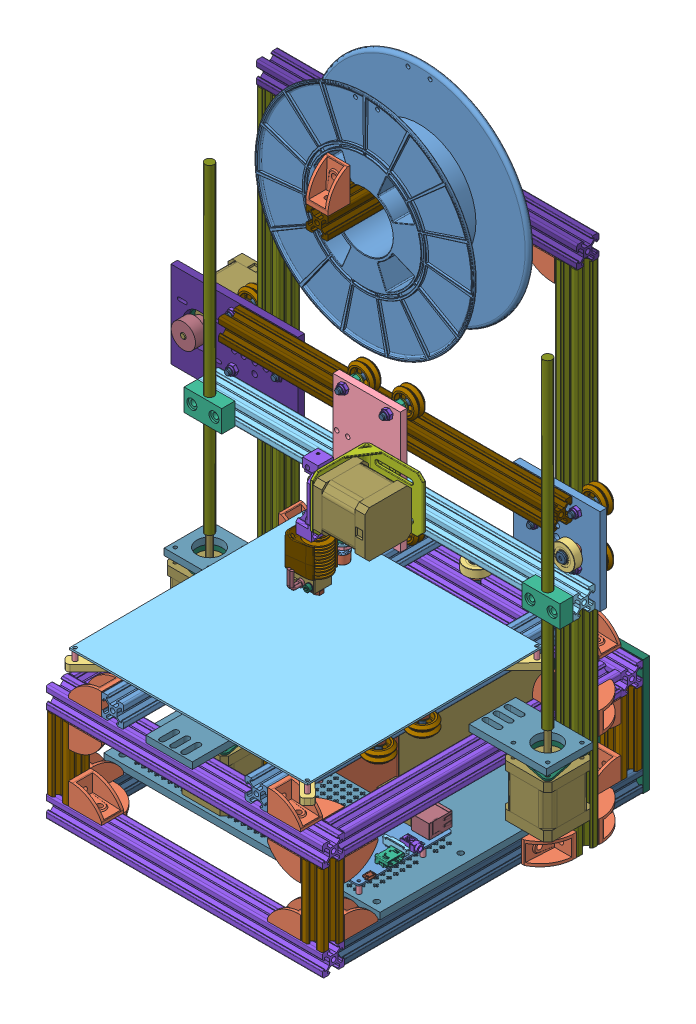
SolidWorks assembly printer, configuration Default. Lengths in mm.
Overall size (437.99 573.71 303.13).
267 component instances, 76 part files, 92 mates.
Components (placement in the parent):
- Y Rail-1: Y Rail [Default] at (13.7265 -1122.1177 248.4377) size (20 20 290)
- Y Rail-2: Y Rail [Default] at (143.7265 -1122.1177 248.4377) size (20 20 290)
- Misumi L bracket-5: Misumi L bracket [Default] at (3.7265 -1132.1177 538.4377) x (0 0 -1) z (0 1 0) size (20 31 21)
- Misumi L bracket-6: Misumi L bracket [Default] at (153.7265 -1132.1177 518.4377) x (0 0 1) z (0 1 0) size (20 31 21)
- y-bed-1: y-bed [Default] at (-21.1202 -1238.0352 260.7176) x (0.99998 0 -0.006342) z (0.006342 0 0.99998) size (222.5 34.74 222.5)
  - y-carriage-1: y-carriage [Default] at (98.8556 128.0325 168.4212) size (222.5 6 222.5)
  - M3 Spacer-1: M3 Spacer [Default] at (-5.6444 134.0325 272.9212) size (4 8 4)
  - M3 Spacer-2: M3 Spacer [Default] at (203.3556 134.0325 63.9212) size (4 8 4)
  - M3 Spacer-3: M3 Spacer [Default] at (203.3556 134.0325 272.9212) size (4 8 4)
  - M3 Spacer-4: M3 Spacer [Default] at (-5.6444 134.0325 63.9212) size (4 8 4)
  - heated-bed-1: heated-bed [Default] at (98.8556 142.0325 168.4212) size (214 1.6 214)
  - Eccentric Delrin Assembly-1: Eccentric Delrin Assembly [Default] at (53.5325 127.0325 167.6503) x (0 -1 0) z (0.219078 0 0.975707) size (31.75 27.59 27.59)
    - Steel Eccentric Spacer-1: Steel Eccentric Spacer [6mm - Mini] at origin size (8.5 9.09 8.71)
    - Precision Shim 10x5x1mm-1: Precision Shim 10x5x1mm [Default] at (6 0 0.79) x (-1 0 0) z (0 0.812589 -0.582837) size (1 10 10)
    - Nylon Insert Hex Locknut M5-1: Nylon Insert Hex Locknut M5 [Default] at (-7 0 0.79) x (0 -0.700969 -0.713192) z (-1 0 0) size (7.68 8.82 4.5)
    - Dual V-Wheel Delrin-1: Dual V-Wheel Delrin [Default] at (11.115 0 0.79) x (0 0.169483 -0.985533) z (1 0 0) size (23.89 23.89 10.23)
    - 5mm Low Profile Socket Head Screw-1: 5mm Low Profile Socket Head Screw [5mm x 30mm Low Profile Screw] at (17.98 0 0.79) x (-1 0 0) z (0 -0.935654 -0.352919) size (31.75 9.5 9.5)
  - Delrin Assembly-1: Delrin Assembly [Default] at (14.0056 122.0325 188.4212) x (0 1 0) z (0.597414 0 0.801933) size (31.75 33.75 33.75)
    - Aluminum Spacer-1: Aluminum Spacer [6mm] at origin size (6 10 10)
    - Precision Shim 10x5x1mm-1: Precision Shim 10x5x1mm [Default] at (-1 0 0) x (1 0 0) z (0 0.993706 0.112022) size (1 10 10)
    - Dual V-Wheel Delrin-1: Dual V-Wheel Delrin [Default] at (-6.115 0 0) x (0 -0.740375 0.672194) z (-1 0 0) size (23.89 23.89 10.23)
    - Nylon Insert Hex Locknut M5-1: Nylon Insert Hex Locknut M5 [Default] at (12 0 0) x (0 -0.231787 0.972767) z (1 0 0) size (7.68 8.82 4.5)
    - 5mm Low Profile Socket Head Screw-1: 5mm Low Profile Socket Head Screw [5mm x 30mm Low Profile Screw] at (-12.98 0 0) x (1 0 0) z (0 0.597414 0.801933) size (31.75 9.5 9.5)
  - Delrin Assembly-2: Delrin Assembly [Default] at (14.0056 122.0325 148.4212) x (0 1 0) z (0.597414 0 0.801933) size (31.75 33.75 33.75)
    - Aluminum Spacer-1: Aluminum Spacer [6mm] at origin size (6 10 10)
    - Precision Shim 10x5x1mm-1: Precision Shim 10x5x1mm [Default] at (-1 0 0) x (1 0 0) z (0 0.993706 0.112022) size (1 10 10)
    - Dual V-Wheel Delrin-1: Dual V-Wheel Delrin [Default] at (-6.115 0 0) x (0 -0.740375 0.672194) z (-1 0 0) size (23.89 23.89 10.23)
    - Nylon Insert Hex Locknut M5-1: Nylon Insert Hex Locknut M5 [Default] at (12 0 0) x (0 -0.231787 0.972767) z (1 0 0) size (7.68 8.82 4.5)
    - 5mm Low Profile Socket Head Screw-1: 5mm Low Profile Socket Head Screw [5mm x 30mm Low Profile Screw] at (-12.98 0 0) x (1 0 0) z (0 0.597414 0.801933) size (31.75 9.5 9.5)
  - Eccentric Delrin Assembly-2: Eccentric Delrin Assembly [Default] at (143.8325 127.0325 167.6503) x (0 -1 0) z (0.219078 0 0.975707) size (31.75 27.59 27.59)
    - Steel Eccentric Spacer-1: Steel Eccentric Spacer [6mm - Mini] at origin size (8.5 9.09 8.71)
    - Precision Shim 10x5x1mm-1: Precision Shim 10x5x1mm [Default] at (6 0 0.79) x (-1 0 0) z (0 0.812589 -0.582837) size (1 10 10)
    - Nylon Insert Hex Locknut M5-1: Nylon Insert Hex Locknut M5 [Default] at (-7 0 0.79) x (0 -0.700969 -0.713192) z (-1 0 0) size (7.68 8.82 4.5)
    - Dual V-Wheel Delrin-1: Dual V-Wheel Delrin [Default] at (11.115 0 0.79) x (0 0.169483 -0.985533) z (1 0 0) size (23.89 23.89 10.23)
    - 5mm Low Profile Socket Head Screw-1: 5mm Low Profile Socket Head Screw [5mm x 30mm Low Profile Screw] at (17.98 0 0.79) x (-1 0 0) z (0 -0.935654 -0.352919) size (31.75 9.5 9.5)
  - Copy of Assem1^y-bed-1: Copy of Assem1^y-bed [Default] at (183.7056 122.0325 148.4212) x (0 1 0) z (0.597414 0 0.801933) size (31.75 33.75 33.75) (virtual)
    - Aluminum Spacer-1: Aluminum Spacer [6mm] at origin size (6 10 10)
    - Precision Shim 10x5x1mm-1: Precision Shim 10x5x1mm [Default] at (-1 0 0) x (1 0 0) z (0 0.993706 0.112022) size (1 10 10)
    - Dual V-Wheel Delrin-1: Dual V-Wheel Delrin [Default] at (-6.115 0 0) x (0 -0.740375 0.672194) z (-1 0 0) size (23.89 23.89 10.23)
    - Nylon Insert Hex Locknut M5-1: Nylon Insert Hex Locknut M5 [Default] at (12 0 0) x (0 -0.231787 0.972767) z (1 0 0) size (7.68 8.82 4.5)
    - 5mm Low Profile Socket Head Screw-1: 5mm Low Profile Socket Head Screw [5mm x 30mm Low Profile Screw] at (-12.98 0 0) x (1 0 0) z (0 0.597414 0.801933) size (31.75 9.5 9.5)
  - Delrin Assembly-4: Delrin Assembly [Default] at (183.7056 122.0325 188.4212) x (0 1 0) z (0.597414 0 0.801933) size (31.75 33.75 33.75)
    - Aluminum Spacer-1: Aluminum Spacer [6mm] at origin size (6 10 10)
    - Precision Shim 10x5x1mm-1: Precision Shim 10x5x1mm [Default] at (-1 0 0) x (1 0 0) z (0 0.993706 0.112022) size (1 10 10)
    - Dual V-Wheel Delrin-1: Dual V-Wheel Delrin [Default] at (-6.115 0 0) x (0 -0.740375 0.672194) z (-1 0 0) size (23.89 23.89 10.23)
    - Nylon Insert Hex Locknut M5-1: Nylon Insert Hex Locknut M5 [Default] at (12 0 0) x (0 -0.231787 0.972767) z (1 0 0) size (7.68 8.82 4.5)
    - 5mm Low Profile Socket Head Screw-1: 5mm Low Profile Socket Head Screw [5mm x 30mm Low Profile Screw] at (-12.98 0 0) x (1 0 0) z (0 0.597414 0.801933) size (31.75 9.5 9.5)
  - 5mm Low Profile Socket Head Screw-1: 5mm Low Profile Socket Head Screw [5mm x 25mm Low Profile Screw] at (98.8556 135.7825 158.4212) x (0 -1 0) z (0.546944 0 -0.837169) size (26.75 9.5 9.5)
  - 5mm Low Profile Socket Head Screw-2: 5mm Low Profile Socket Head Screw [5mm x 25mm Low Profile Screw] at (98.8556 135.7825 178.4212) x (0 -1 0) z (0.546944 0 -0.837169) size (26.75 9.5 9.5)
  - Nylon Insert Hex Locknut M5-1: Nylon Insert Hex Locknut M5 [Default] at (98.8556 128.0325 178.4212) x (1 0 0) z (0 -1 0) size (7.68 8.82 4.5)
  - Nylon Insert Hex Locknut M5-2: Nylon Insert Hex Locknut M5 [Default] at (98.8556 113.3925 178.4212) x (1 0 0) z (0 -1 0) size (7.68 8.82 4.5)
  - Nylon Insert Hex Locknut M5-3: Nylon Insert Hex Locknut M5 [Default] at (98.8556 113.3925 158.4212) x (1 0 0) z (0 -1 0) size (7.68 8.82 4.5)
  - Nylon Insert Hex Locknut M5-4: Nylon Insert Hex Locknut M5 [Default] at (98.8556 128.0325 158.4212) x (1 0 0) z (0 -1 0) size (7.68 8.82 4.5)
- y-bracket-1: y-bracket [Default] at (76.4863 -1102.506 533.3758) x (-1 0 0) z (0 -1 0) size (93.79 93.79 71)
  - NEMA17_48-1: NEMA17_48 [Default] at (11.6367 44.9381 35.5117) x (-1 0 0) z (0 0 -1) size (42 42 71)
  - GT2 Pulley-1: GT2 Pulley [Default] at (11.6367 44.9381 21.5117) x (-0.999479 -0.032284 0) z (-0.032284 0.999479 0) size (22 17 22)
  - Z Stepper Mount-1: Z Stepper Mount [Default] at (11.6367 29.9381 23.6117) x (1 0 0) z (0 -1 0) size (42 6 70)
  - Stepper Damper-1: Stepper Damper [Default] at (11.6365 44.9378 35.5117) x (0.707107 -0.707107 0) z (0.707107 0.707107 0) size (51.85 6.11 80.79)
- Z Rail-2: Z Rail [Default] at (213.7265 -1237.1177 318.4377) x (0 0 -1) z (0 1 0) size (20 20 460)
- X Axis-1: X Axis [Default] at (-95.8785 -1062.7406 209.5476) size (422.73 154.29 145.41) (flexible)
  - X Motor-1: X Motor [Default] at (-35.3266 39.1515 56.2965) size (149.33 96.33 71)
    - NEMA17_48-1: NEMA17_48 [Default] at (18.5315 36.8987 58.8087) size (42 42 71)
    - X Stepper Mount-1: X Stepper Mount [Default] at (71.5315 36.8987 64.7087) x (1 0 0) z (0 -1 0) size (115 6 78.4)
    - GT2 Pulley-1: GT2 Pulley [Default] at (18.5315 36.8987 72.2337) x (0.991394 0.130915 0) z (-0.130915 0.991394 0) size (22 17 22)
    - Delrin Assembly-1: Delrin Assembly [Default] at (52.9627 66.0979 58.7087) x (0 0 1) z (0.923728 0.383049 0) size (31.75 33.75 33.75)
      - Aluminum Spacer-1: Aluminum Spacer [6mm] at origin size (6 10 10)
      - Precision Shim 10x5x1mm-1: Precision Shim 10x5x1mm [Default] at (-1 0 0) x (1 0 0) z (0 0.993706 0.112022) size (1 10 10)
      - Dual V-Wheel Delrin-1: Dual V-Wheel Delrin [Default] at (-6.115 0 0) x (0 -0.740375 0.672194) z (-1 0 0) size (23.89 23.89 10.23)
      - Nylon Insert Hex Locknut M5-1: Nylon Insert Hex Locknut M5 [Default] at (12 0 0) x (0 -0.231787 0.972767) z (1 0 0) size (7.68 8.82 4.5)
      - 5mm Low Profile Socket Head Screw-1: 5mm Low Profile Socket Head Screw [5mm x 30mm Low Profile Screw] at (-12.98 0 0) x (1 0 0) z (0 0.597414 0.801933) size (31.75 9.5 9.5)
    - Delrin Assembly-2: Delrin Assembly [Default] at (52.9627 22.6994 58.7087) x (0 0 1) z (0.923728 0.383049 0) size (31.75 33.75 33.75)
      - Aluminum Spacer-1: Aluminum Spacer [6mm] at origin size (6 10 10)
      - Precision Shim 10x5x1mm-1: Precision Shim 10x5x1mm [Default] at (-1 0 0) x (1 0 0) z (0 0.993706 0.112022) size (1 10 10)
      - Dual V-Wheel Delrin-1: Dual V-Wheel Delrin [Default] at (-6.115 0 0) x (0 -0.740375 0.672194) z (-1 0 0) size (23.89 23.89 10.23)
      - Nylon Insert Hex Locknut M5-1: Nylon Insert Hex Locknut M5 [Default] at (12 0 0) x (0 -0.231787 0.972767) z (1 0 0) size (7.68 8.82 4.5)
      - 5mm Low Profile Socket Head Screw-1: 5mm Low Profile Socket Head Screw [5mm x 30mm Low Profile Screw] at (-12.98 0 0) x (1 0 0) z (0 0.597414 0.801933) size (31.75 9.5 9.5)
    - Eccentric Delrin Assembly-1: Eccentric Delrin Assembly [Default] at (91.8727 36.8987 61.2087) x (0 0 -1) z (1 0 0) size (31.75 27.59 27.59)
      - Steel Eccentric Spacer-1: Steel Eccentric Spacer [6mm - Mini] at origin size (8.5 9.09 8.71)
      - Precision Shim 10x5x1mm-1: Precision Shim 10x5x1mm [Default] at (6 0 0.79) x (-1 0 0) z (0 0.812589 -0.582837) size (1 10 10)
      - Nylon Insert Hex Locknut M5-1: Nylon Insert Hex Locknut M5 [Default] at (-7 0 0.79) x (0 -0.700969 -0.713192) z (-1 0 0) size (7.68 8.82 4.5)
      - Dual V-Wheel Delrin-1: Dual V-Wheel Delrin [Default] at (11.115 0 0.79) x (0 0.169483 -0.985533) z (1 0 0) size (23.89 23.89 10.23)
      - 5mm Low Profile Socket Head Screw-1: 5mm Low Profile Socket Head Screw [5mm x 30mm Low Profile Screw] at (17.98 0 0.79) x (-1 0 0) z (0 -0.935654 -0.352919) size (31.75 9.5 9.5)
    - Stepper Damper-1: Stepper Damper [Default] at (18.5317 36.8985 58.8087) x (0.707107 0.707107 0) z (0.707107 -0.707107 0) size (51.85 6.11 80.79)
  - Upper X Rail-1: Upper X Rail [Default] at (23.5992 105.2494 137.0052) x (0 0 1) z (1 0 0) size (20 20 300)
  - X End-1: X End [Default] at (349.9804 66.2549 121.0052) x (-1 0 0) z (0 1 0) size (78.4 6 78.4)
  - Delrin Assembly-1: Delrin Assembly [Default] at (328.1737 61.8509 115.0052) x (0 0 1) z (-0.14439 -0.989521 0) size (31.75 33.75 33.75)
    - Aluminum Spacer-1: Aluminum Spacer [6mm] at origin size (6 10 10)
    - Precision Shim 10x5x1mm-1: Precision Shim 10x5x1mm [Default] at (-1 0 0) x (1 0 0) z (0 0.993706 0.112022) size (1 10 10)
    - Dual V-Wheel Delrin-1: Dual V-Wheel Delrin [Default] at (-6.115 0 0) x (0 -0.740375 0.672194) z (-1 0 0) size (23.89 23.89 10.23)
    - Nylon Insert Hex Locknut M5-1: Nylon Insert Hex Locknut M5 [Default] at (12 0 0) x (0 -0.231787 0.972767) z (1 0 0) size (7.68 8.82 4.5)
    - 5mm Low Profile Socket Head Screw-1: 5mm Low Profile Socket Head Screw [5mm x 30mm Low Profile Screw] at (-12.98 0 0) x (1 0 0) z (0 0.597414 0.801933) size (31.75 9.5 9.5)
  - Delrin Assembly-2: Delrin Assembly [Default] at (328.1737 105.2494 115.0052) x (0 0 1) z (-1 0 0) size (31.75 33.75 33.75)
    - Aluminum Spacer-1: Aluminum Spacer [6mm] at origin size (6 10 10)
    - Precision Shim 10x5x1mm-1: Precision Shim 10x5x1mm [Default] at (-1 0 0) x (1 0 0) z (0 0.993706 0.112022) size (1 10 10)
    - Dual V-Wheel Delrin-1: Dual V-Wheel Delrin [Default] at (-6.115 0 0) x (0 -0.740375 0.672194) z (-1 0 0) size (23.89 23.89 10.23)
    - Nylon Insert Hex Locknut M5-1: Nylon Insert Hex Locknut M5 [Default] at (12 0 0) x (0 -0.231787 0.972767) z (1 0 0) size (7.68 8.82 4.5)
    - 5mm Low Profile Socket Head Screw-1: 5mm Low Profile Socket Head Screw [5mm x 30mm Low Profile Screw] at (-12.98 0 0) x (1 0 0) z (0 0.597414 0.801933) size (31.75 9.5 9.5)
  - Eccentric Delrin Assembly-1: Eccentric Delrin Assembly [Default] at (289.2035 76.3528 117.5052) x (0 0 -1) z (-0.923728 -0.383049 0) size (31.75 27.59 27.59)
    - Steel Eccentric Spacer-1: Steel Eccentric Spacer [6mm - Mini] at origin size (8.5 9.09 8.71)
    - Precision Shim 10x5x1mm-1: Precision Shim 10x5x1mm [Default] at (6 0 0.79) x (-1 0 0) z (0 0.812589 -0.582837) size (1 10 10)
    - Nylon Insert Hex Locknut M5-1: Nylon Insert Hex Locknut M5 [Default] at (-7 0 0.79) x (0 -0.700969 -0.713192) z (-1 0 0) size (7.68 8.82 4.5)
    - Dual V-Wheel Delrin-1: Dual V-Wheel Delrin [Default] at (11.115 0 0.79) x (0 0.169483 -0.985533) z (1 0 0) size (23.89 23.89 10.23)
    - 5mm Low Profile Socket Head Screw-1: 5mm Low Profile Socket Head Screw [5mm x 30mm Low Profile Screw] at (17.98 0 0.79) x (-1 0 0) z (0 -0.935654 -0.352919) size (31.75 9.5 9.5)
  - 5mm Low Profile Socket Head Screw-1: 5mm Low Profile Socket Head Screw [5mm x 30mm Low Profile Screw] at (328.1737 76.0502 142.1052) x (0 0 -1) z (1 0 0) size (31.75 9.5 9.5)
  - Nylon Spacer-1: Nylon Spacer [.25 inch] at (328.1737 76.0502 133.3552) x (0 0 -1) z (1 0 0) size (6.35 7.94 7.94)
  - Ball Bearing 608Z-1: Ball Bearing 608Z [Default] at (328.1737 76.0502 136.8552) x (0 0 -1) z (1 0 0) size (7 22 22)
  - Nylon Insert Hex Locknut M5-1: Nylon Insert Hex Locknut M5 [Default] at (328.1737 76.0502 121.0052) x (-0.923728 -0.383049 0) z (0 0 -1) size (7.68 8.82 4.5)
  - X Carriage-1: X Carriage [Default] at (165.6175 76.0502 149.1202) x (1 0 0) z (0 -1 0) size (61.08 6 110.03)
  - Eccentric Delrin Assembly-2: Eccentric Delrin Assembly [Default] at (185.1373 125.7275 148.1202) x (0 0 -1) z (0.607741 -0.794136 0) size (31.75 27.59 27.59)
    - Steel Eccentric Spacer-1: Steel Eccentric Spacer [6mm - Mini] at origin size (8.5 9.09 8.71)
    - Precision Shim 10x5x1mm-1: Precision Shim 10x5x1mm [Default] at (6 0 0.79) x (-1 0 0) z (0 0.812589 -0.582837) size (1 10 10)
    - Nylon Insert Hex Locknut M5-1: Nylon Insert Hex Locknut M5 [Default] at (-7 0 0.79) x (0 -0.700969 -0.713192) z (-1 0 0) size (7.68 8.82 4.5)
    - Dual V-Wheel Delrin-1: Dual V-Wheel Delrin [Default] at (11.115 0 0.79) x (0 0.169483 -0.985533) z (1 0 0) size (23.89 23.89 10.23)
    - 5mm Low Profile Socket Head Screw-1: 5mm Low Profile Socket Head Screw [5mm x 30mm Low Profile Screw] at (17.98 0 0.79) x (-1 0 0) z (0 -0.935654 -0.352919) size (31.75 9.5 9.5)
  - Delrin Assembly-3: Delrin Assembly [Default] at (145.6175 27.0002 143.1202) x (0 0 1) z (-1 0 0) size (31.75 33.75 33.75)
    - Aluminum Spacer-1: Aluminum Spacer [6mm] at origin size (6 10 10)
    - Precision Shim 10x5x1mm-1: Precision Shim 10x5x1mm [Default] at (-1 0 0) x (1 0 0) z (0 0.993706 0.112022) size (1 10 10)
    - Dual V-Wheel Delrin-1: Dual V-Wheel Delrin [Default] at (-6.115 0 0) x (0 -0.740375 0.672194) z (-1 0 0) size (23.89 23.89 10.23)
    - Nylon Insert Hex Locknut M5-1: Nylon Insert Hex Locknut M5 [Default] at (12 0 0) x (0 -0.231787 0.972767) z (1 0 0) size (7.68 8.82 4.5)
    - 5mm Low Profile Socket Head Screw-1: 5mm Low Profile Socket Head Screw [5mm x 30mm Low Profile Screw] at (-12.98 0 0) x (1 0 0) z (0 0.597414 0.801933) size (31.75 9.5 9.5)
  - Delrin Assembly-4: Delrin Assembly [Default] at (185.6175 27.0002 143.1202) x (0 0 1) z (-1 0 0) size (31.75 33.75 33.75)
    - Aluminum Spacer-1: Aluminum Spacer [6mm] at origin size (6 10 10)
    - Precision Shim 10x5x1mm-1: Precision Shim 10x5x1mm [Default] at (-1 0 0) x (1 0 0) z (0 0.993706 0.112022) size (1 10 10)
    - Dual V-Wheel Delrin-1: Dual V-Wheel Delrin [Default] at (-6.115 0 0) x (0 -0.740375 0.672194) z (-1 0 0) size (23.89 23.89 10.23)
    - Nylon Insert Hex Locknut M5-1: Nylon Insert Hex Locknut M5 [Default] at (12 0 0) x (0 -0.231787 0.972767) z (1 0 0) size (7.68 8.82 4.5)
    - 5mm Low Profile Socket Head Screw-1: 5mm Low Profile Socket Head Screw [5mm x 30mm Low Profile Screw] at (-12.98 0 0) x (1 0 0) z (0 0.597414 0.801933) size (31.75 9.5 9.5)
  - Lower X Rail-1: Lower X Rail [Default] at (4.4042 46.8509 137.0052) x (0 0 -1) z (1 0 0) size (20 20 340)
  - Nut Block 8mm Acme-1: Nut Block 8mm Acme [Default] at (21.4042 36.8509 153.0052) x (1 0 0) z (0 -1 0) size (34 12 20)
  - Nut Block 8mm Acme-2: Nut Block 8mm Acme [Default] at (327.4042 36.8509 153.0052) x (1 0 0) z (0 -1 0) size (34 12 20)
  - Eccentric Delrin Assembly-3: Eccentric Delrin Assembly [Default] at (144.8275 125.1002 148.1202) x (0 0 -1) z (1 0 0) size (31.75 27.59 27.59)
    - Steel Eccentric Spacer-1: Steel Eccentric Spacer [6mm - Mini] at origin size (8.5 9.09 8.71)
    - Precision Shim 10x5x1mm-1: Precision Shim 10x5x1mm [Default] at (6 0 0.79) x (-1 0 0) z (0 0.812589 -0.582837) size (1 10 10)
    - Nylon Insert Hex Locknut M5-1: Nylon Insert Hex Locknut M5 [Default] at (-7 0 0.79) x (0 -0.700969 -0.713192) z (-1 0 0) size (7.68 8.82 4.5)
    - Dual V-Wheel Delrin-1: Dual V-Wheel Delrin [Default] at (11.115 0 0.79) x (0 0.169483 -0.985533) z (1 0 0) size (23.89 23.89 10.23)
    - 5mm Low Profile Socket Head Screw-1: 5mm Low Profile Socket Head Screw [5mm x 30mm Low Profile Screw] at (17.98 0 0.79) x (-1 0 0) z (0 -0.935654 -0.352919) size (31.75 9.5 9.5)
  - Extruder-1: Extruder [Default] at (232.6446 90.5173 147.8987) x (0 -1 0) z (-1 0 0) size (110.43 53.9 89.7)
    - stepper motor mount-1: stepper motor mount [Default] at (17.4671 41.9715 62.2771) size (50.16 51.25 53.25)
    - NEMA17_48-1: NEMA17_48 [Default] at (17.4671 41.9715 59.6771) size (42 42 71)
    - extruder-2: extruder [Default] at (17.0666 41.9725 62.2771) x (0 1 0) z (0 0 1) size (42 57.13 22.4)
    - E3D All Metal Hotend V6-1: E3D All Metal Hotend V6 [Default] at (80.7686 46.3695 71.7134) x (0 0 -1) z (1 0 0) size (38.16 34.25 62.3)
      - E3D v6 HotEnd - Heatsink-1: E3D v6 HotEnd - Heatsink [Default] at origin size (22.3 22.3 42.7)
      - E3D v6 HotEnd - Heatbreak-1: E3D v6 HotEnd - Heatbreak [Default] at (0 0 7.1) size (7 7 21.9)
      - E3D v6 HotEnd - Nozzle-1: E3D v6 HotEnd - Nozzle [Default] at (0 0 17.6) x (0.866025 0.5 0) z (0 0 1) size (8.08 7 12.5)
      - E3D v6 HotEnd - Heat Block-1: E3D v6 HotEnd - Heat Block [Default] at (-15.5 8 13.6) x (1 0 0) z (0 1 0) size (20 11.5 16)
      - Ceramic Cartridge Heater-1: Ceramic Cartridge Heater [Default] at (-7 10 9.6) x (1 0 0) z (0 1 0) size (6 18 29.25)
      - Thermistor-1: Thermistor [Default] at (2.5 3.65 11.6) x (0.903857 0 0.427835) z (0 -1 0) size (4.52 1.5 4.65)
      - HEXAGON SOCKET HEAD CAP SCREWS_SCB3-4-1: HEXAGON SOCKET HEAD CAP SCREWS_SCB3-4 [Default] at (1 9 8.8) x (0.999538 0 0.030402) z (0 1 0) size (5.5 5.5 7)
      - HEXAGON SOCKET HEAD CAP SCREWS_SCB3-10-1: HEXAGON SOCKET HEAD CAP SCREWS_SCB3-10 [Default] at (-13 0 13.6) size (5.5 5.5 13)
      - Flat Washers_PWF3-1: Flat Washers_PWF3 [Default] at (1 9 8.8) x (1 0 0) z (0 1 0) size (6 6 0.5)
      - E3D-v6 Fan Duct-1: E3D-v6 Fan Duct [Default] x (1 0 0) z (0 1 0) size (22.31 30.04 30)
      - Fan-DC-KDE0503PFB3-Promoco_Fan-DC-KDE0503PFB3-Promoco-1: Fan-DC-KDE0503PFB3-Promoco_Fan-DC-KDE0503PFB3-Promoco [Default] at (-15 0 -15) x (0 0 -1) z (-1 0 0) size (30 30 10) (hidden)
        - Fan-House-30x30x10-Promoco_Fan-House-KDE0503PFB3-Promoco-1: Fan-House-30x30x10-Promoco_Fan-House-KDE0503PFB3-Promoco [Default] at origin size (30 30 10)
        - Fan-30x30x10-Promoco_Fan-KDE0503PFB3-Promoco-1: Fan-30x30x10-Promoco_Fan-KDE0503PFB3-Promoco [Default] x (0 0 -1) z (-0.999131 0.04169 0) size (8.5 27.91 28)
      - Self Tapping Screws - Pan Head_CSPTRSA-SUS-TP3-16-1: Self Tapping Screws - Pan Head_CSPTRSA-SUS-TP3-16 [Default] at (-25 -12 -27) size (18.01 5.5 5.5) (hidden)
      - Self Tapping Screws - Pan Head_CSPTRSA-SUS-TP3-16-2: Self Tapping Screws - Pan Head_CSPTRSA-SUS-TP3-16 [Default] at (-25 12 -27) size (18.01 5.5 5.5) (hidden)
      - Self Tapping Screws - Pan Head_CSPTRSA-SUS-TP3-16-3: Self Tapping Screws - Pan Head_CSPTRSA-SUS-TP3-16 [Default] at (-25 12 -3) size (18.01 5.5 5.5) (hidden)
      - Self Tapping Screws - Pan Head_CSPTRSA-SUS-TP3-16-4: Self Tapping Screws - Pan Head_CSPTRSA-SUS-TP3-16 [Default] at (-25 -12 -3) size (18.01 5.5 5.5) (hidden)
  - LJ12A3-4-Z-BY-1: LJ12A3-4-Z-BY [Default] at (168.9845 19.2918 174.3445) x (0.423972 0 -0.905675) z (0 1 0) size (28.44 28.44 65)
    - LJ12A3-4-Z-BY-1-1: LJ12A3-4-Z-BY-1 [Default] at (0.8756 15.1692 -10.7678) size (12.8 13.04 50.55)
    - LJ12A3-4-Z-BY-2-2: LJ12A3-4-Z-BY-2 [Default] at (0.8756 15.1692 -18.7678) x (1 0 0) z (0 1 0) size (11 10 11)
    - LJ12A3-4-Z-BY-3-1: LJ12A3-4-Z-BY-3 [Default] at (0.8756 15.1692 41.2322) x (1 0 0) z (0 -1 0) size (11 9 11)
    - LJ12A3-4-Z-BY-4-1: LJ12A3-4-Z-BY-4 [Default] at (0.8756 15.1692 -4.7678) x (-0.69421 -0.719772 0) z (0 0 1) size (17 19.63 6)
    - LJ12A3-4-Z-BY-5-1: LJ12A3-4-Z-BY-5 [Default] at (0.8756 15.1692 -0.7678) size (22 22 2.5)
    - LJ12A3-4-Z-BY-5-2: LJ12A3-4-Z-BY-5 [Default] at (0.8756 15.1692 11.7322) x (-0.933046 0.359756 0) z (0 0 1) size (22 22 2.5)
    - LJ12A3-4-Z-BY-4-2: LJ12A3-4-Z-BY-4 [Default] at (0.8756 15.1692 14.2322) x (0.033197 -0.999449 0) z (0 0 1) size (17 19.63 6)
  - Probe Mount-1: Probe Mount [Default] at (163.6175 26.024 155.1202) x (1 0 0) z (0 -1 0) size (30 23.6 10)
  - Extruder Spacer-1: Extruder Spacer [Default] at (187.6175 73.0502 155.1202) x (1 0 0) z (0 -1 0) size (17 4.5 38)
- Frame Base-2: Frame Base [Default] at (-51.2955 -1090.6733 303.3085) size (250 105.4 296)
  - Frame-1: Frame [Default] at (15.0219 -51.4444 -34.8708) size (20 20 250)
  - Frame-2: Frame [Default] at (255.0219 -51.4444 -44.8708) x (0 0 1) z (-1 0 0) size (20 20 250)
  - Frame-3: Frame [Default] at (245.0219 -51.4444 -34.8708) size (20 20 250)
  - Frame-4: Frame [Default] at (255.0219 -51.4444 225.1292) x (0 0 1) z (-1 0 0) size (20 20 250)
  - Misumi L bracket-1: Misumi L bracket [Default] at (235.0219 -61.4444 -34.8708) x (0 1 0) z (0 0 1) size (20 31 21)
  - Misumi L bracket-2: Misumi L bracket [Default] at (235.0219 -41.4444 215.1292) x (0 -1 0) z (0 0 -1) size (20 31 21)
  - Misumi L bracket-3: Misumi L bracket [Default] at (25.0219 -41.4444 -34.8708) x (0 -1 0) z (0 0 1) size (20 31 21)
  - Misumi L bracket-4: Misumi L bracket [Default] at (25.0219 -61.4444 215.1292) x (0 1 0) z (0 0 -1) size (20 31 21)
  - Base Supports-1: Base Supports [Default] at (15.0219 -126.4444 225.1292) x (1 0 0) z (0 1 0) size (20 20 65)
  - Base Supports-2: Base Supports [Default] at (15.0219 -126.4444 -44.8708) x (1 0 0) z (0 1 0) size (20 20 65)
  - Base Supports-3: Base Supports [Default] at (245.0219 -126.4444 225.1292) x (1 0 0) z (0 1 0) size (20 20 65)
  - Base Supports-4: Base Supports [Default] at (245.0219 -61.4444 -44.8708) x (1 0 0) z (0 -1 0) size (20 20 65)
  - Frame-5: Frame [Default] at (255.0219 -136.4444 225.1292) x (0 0 1) z (-1 0 0) size (20 20 250)
  - Frame Long-1: Frame Long [Default] at (245.0219 -136.4444 -54.8708) size (20 20 270)
  - Frame Long-2: Frame Long [Default] at (15.0219 -136.4444 -54.8708) size (20 20 270)
  - ATX Power Supply v1.0-1: ATX Power Supply v1.0 [Default] at (100.0219 -146.8444 15.6292) x (-1 0 0) z (0 0 -1) size (150 86.42 152)
    - Box v1.0 - ATX Power Supply-1: Box v1.0 - ATX Power Supply [Default] at origin size (150 84.7 141.01)
    - Cover v1.0 - ATX Power Supply-1: Cover v1.0 - ATX Power Supply [Default] at (0 2.9 0) size (150 82.63 140.5)
    - Grelha Prot Vent 120-1: Grelha Prot Vent 120 [Default] at (0 85.55 0) x (-1 0 0) z (0 -1 0) size (115.85 114.72 3.29)
    - IEC Plug-1: IEC Plug [Default] at (44.5 24 70.5) size (49.54 22 31)
    - Switch on-off-1: Switch on-off [Default] at (36 54.5 62.5) x (0 -1 0) z (0 0 1) size (15 21 21.45)
    - Ventax 119x119x26-1: Ventax 119x119x26 [Default] at (0 60.95 0) x (1 0 0) z (0 -1 0) size (124.36 129.72 26)
    - Casq-1: Casq [Default] at (61.3 45 -58.5) x (1 0 0) z (0 1 0) size (24 17 24)
  - Misumi L bracket-5: Misumi L bracket [Default] at (25.0219 -146.4444 215.1292) x (0 1 0) z (0 0 -1) size (20 31 21)
  - Misumi L bracket-6: Misumi L bracket [Default] at (235.0219 -126.4444 215.1292) x (1 0 0) z (0 1 0) size (20 31 21)
  - Misumi L bracket-7: Misumi L bracket [Default] at (235.0219 -126.4444 215.1292) x (0 -1 0) z (0 0 -1) size (20 31 21)
  - Misumi L bracket-8: Misumi L bracket [Default] at (235.0219 -61.4444 -34.8708) x (1 0 0) z (0 -1 0) size (20 31 21)
  - Misumi L bracket-9: Misumi L bracket [Default] at (255.0219 -126.4444 -34.8708) x (-1 0 0) z (0 1 0) size (20 31 21)
  - Misumi L bracket-10: Misumi L bracket [Default] at (25.0219 -61.4444 215.1292) x (-1 0 0) z (0 -1 0) size (20 31 21)
  - Misumi L bracket-11: Misumi L bracket [Default] at (25.0219 -126.4444 -34.8708) x (-1 0 0) z (0 1 0) size (20 31 21)
  - Misumi L bracket-12: Misumi L bracket [Default] at (5.0219 -61.4444 -34.8708) x (1 0 0) z (0 -1 0) size (20 31 21)
  - Misumi L bracket-13: Misumi L bracket [Default] at (5.0219 -126.4444 215.1292) x (1 0 0) z (0 1 0) size (20 31 21)
  - Misumi L bracket-14: Misumi L bracket [Default] at (25.0219 -61.4444 235.1292) x (0 0 -1) z (0 -1 0) size (20 31 21)
  - Misumi L bracket-15: Misumi L bracket [Default] at (255.0219 -61.4444 215.1292) x (-1 0 0) z (0 -1 0) size (20 31 21)
  - Misumi L bracket-16: Misumi L bracket [Default] at (235.0219 -61.4444 215.1292) x (0 0 1) z (0 -1 0) size (20 31 21)
  - Misumi L bracket-17: Misumi L bracket [Default] at (235.0219 -126.4444 235.1292) x (0 0 -1) z (0 1 0) size (20 31 21)
  - Misumi L bracket-18: Misumi L bracket [Default] at (25.0219 -126.4444 215.1292) x (0 0 1) z (0 1 0) size (20 31 21)
  - MiniRambo-1: MiniRambo [Default] at (77.5224 -112.4444 138.2459) size (105 2 71)
  - RaspberryPi2 model B SW-1: RaspberryPi2 model B SW [Default] at (205.5219 -111.1444 138.2459) x (0 0 -1) z (1 0 0) size (89.62 18.75 58.3)
    - Mainboard2-1: Mainboard2 [Default] at origin size (85 1.3 56)
    - GPIO-1: GPIO [Default] at (-11.37 0 -24.5) x (0 0 1) z (-1 0 0) size (5 11.5 50.8)
    - Processor-1: Processor [Default] at (-15.5 0 -3) x (0 0 1) z (-1 0 0) size (14 1 14)
    - GPU-1: GPU [Default] at (15.25 0 -5.75) x (0 0 1) z (-1 0 0) size (9.1 1 9.1)
    - CameraAssembly-4: CameraAssembly [Default] at (10.0885 -2.9159 16.55) x (-1 0 0) z (0 0 -1) size (5 5.5 22.1)
    - CameraAssembly-3: CameraAssembly [Default] at (-46.3885 -2.9159 0) size (5 5.5 22.1)
    - hdmi-1: hdmi [Default] at (-10.2 0.27 29.3) size (15.14 8.38 12.15)
    - RAM-1: RAM [Default] at (0.5 -2.3 -6) x (0 0 1) z (-1 0 0) size (12 1 12)
    - Audio-1: Audio [Default] at (10.9 0.15 21.75) size (7 6 14.8)
    - MicroSDSocket-1: MicroSDSocket [Default] at (-34.5 -1.3 -0.7) x (0 0 -1) z (-1 0 0) size (13 1.3 14)
    - MicroSD-1: MicroSD [Default] at (-37 -2.3 0.1) x (0 0 1) z (-1 0 0) size (11 1 15)
    - micro USB2-1: micro USB2 [Default] at (-17.2704 -5.0969 44.9026) size (7.99 2.94 5.43)
    - usb double-1: usb double [Default] at (30.38 -0.09 -18.85) x (0 0 -1) z (1 0 0) size (15.6 18.75 17.92)
    - usb double-2: usb double [Default] at (30.38 -0.09 -1.25) x (0 0 -1) z (1 0 0) size (15.6 18.75 17.92)
    - RJ45-LED-1: RJ45-LED [Default] at (34.11 7.4 17.348) x (1 0 0) z (0 -1 0) size (20.75 17.99 14.09)
  - Electronics Platform-1: Electronics Platform [Default] at (129.698 -120.4444 138.2459) x (-1 0 0) z (0 0 1) size (250 6 175)
  - M3 Spacer-1: M3 Spacer [Default] at (230.0219 -120.4444 177.2459) x (0.996702 0 0.081143) z (-0.081143 0 0.996702) size (4 8 4)
  - M3 Spacer-2: M3 Spacer [Default] at (181.0219 -120.4444 119.2459) x (0.707838 0 0.706374) z (-0.706374 0 0.707838) size (4 8 4)
  - M3 Spacer-3: M3 Spacer [Default] at (230.0219 -120.4444 119.2459) x (0.665006 0 -0.746838) z (0.746838 0 0.665006) size (4 8 4)
  - M3 Spacer-4: M3 Spacer [Default] at (181.0219 -120.4444 177.2459) x (0.824752 0 0.565494) z (-0.565494 0 0.824752) size (4 8 4)
  - M3 Spacer-5: M3 Spacer [Default] at (125.0224 -120.4444 107.7459) x (0.921904 0 -0.387417) z (0.387417 0 0.921904) size (4 8 4)
  - M3 Spacer-6: M3 Spacer [Default] at (125.0224 -120.4444 168.7459) x (0.747282 0 -0.664507) z (0.664507 0 0.747282) size (4 8 4)
  - M3 Spacer-7: M3 Spacer [Default] at (30.0224 -120.4444 107.7459) x (0.861641 0 -0.507518) z (0.507518 0 0.861641) size (4 8 4)
  - M3 Spacer-8: M3 Spacer [Default] at (30.0224 -120.4444 168.7459) x (-0.841758 0 -0.539856) z (0.539856 0 -0.841758) size (4 8 4)
  - PSU Plate-1: PSU Plate [Default] at (130.0219 -93.9444 -54.8708) x (-1 0 0) z (0 -1 0) size (250 6 105)
- Z Rail-3: Z Rail [Default] at (-56.2735 -777.1177 318.4377) x (1 0 0) z (0 -1 0) size (20 20 460)
- Z Stepper-1: Z Stepper [Default] at (-109.9322 -1193.6697 336.1842) x (0 0 1) z (0 1 0) size (93.79 93.79 362)
  - NEMA17_48-1: NEMA17_48 [Default] at (26.3685 35.4579 55.652) size (42 42 71)
  - Z Stepper Mount-1: Z Stepper Mount [Default] at (26.3685 50.4579 67.552) x (1 0 0) z (0 1 0) size (42 6 70)
  - 8mm TR8_8 Leadscrew-1: 8mm TR8_8 Leadscrew [250mm - 8mm TR8_8 Leadscrew] at (26.3685 35.4579 369.652) size (8 8 291)
  - Stepper Damper-1: Stepper Damper [Default] at (26.3688 35.4581 55.652) x (0.707107 -0.707107 0) z (-0.707107 -0.707107 0) size (51.85 6.11 80.79)
- Z Stepper-2: Z Stepper [Default] at (266.9836 -1193.6697 388.9213) x (0 0 -1) z (0 1 0) size (93.79 93.79 362)
  - NEMA17_48-1: NEMA17_48 [Default] at (26.3685 35.4579 55.652) size (42 42 71)
  - Z Stepper Mount-1: Z Stepper Mount [Default] at (26.3685 50.4579 67.552) x (1 0 0) z (0 1 0) size (42 6 70)
  - 8mm TR8_8 Leadscrew-1: 8mm TR8_8 Leadscrew [250mm - 8mm TR8_8 Leadscrew] at (26.3685 35.4579 369.652) size (8 8 291)
  - Stepper Damper-1: Stepper Damper [Default] at (26.3688 35.4581 55.652) x (0.707107 -0.707107 0) z (-0.707107 -0.707107 0) size (51.85 6.11 80.79)
- Crossbar-1: Crossbar [Default] at (223.7265 -767.1177 318.4377) x (0 0 1) z (-1 0 0) size (20 20 290)
- Misumi L bracket-7: Misumi L bracket [Default] at (153.7265 -1132.1177 248.4377) x (0 0 1) z (0 1 0) size (20 31 21)
- Misumi L bracket-8: Misumi L bracket [Default] at (3.7265 -1132.1177 268.4377) x (0 0 -1) z (0 1 0) size (20 31 21)
- Misumi L bracket-9: Misumi L bracket [Default] at (-46.2735 -777.1177 328.4377) x (0 0 -1) z (0 -1 0) size (20 31 21)
- Misumi L bracket-10: Misumi L bracket [Default] at (203.7265 -777.1177 308.4377) x (0 0 1) z (0 -1 0) size (20 31 21)
- Misumi L bracket-11: Misumi L bracket [Default] at (-46.2735 -1217.1177 328.4377) x (0 -1 0) z (-1 0 0) size (20 31 21)
- Misumi L bracket-12: Misumi L bracket [Default] at (-46.2735 -1237.1177 308.4377) x (0 1 0) z (-1 0 0) size (20 31 21)
- Misumi L bracket-13: Misumi L bracket [Default] at (-46.2735 -1155.1177 308.4377) x (0 1 0) z (-1 0 0) size (20 31 21)
- Misumi L bracket-14: Misumi L bracket [Default] at (203.7265 -1237.1177 328.4377) x (0 1 0) z (1 0 0) size (20 31 21)
- Misumi L bracket-15: Misumi L bracket [Default] at (203.7265 -1217.1177 308.4377) x (0 -1 0) z (1 0 0) size (20 31 21)
- Misumi L bracket-16: Misumi L bracket [Default] at (-46.2735 -1132.1177 328.4377) x (0 0 -1) z (1 0 0) size (20 31 21)
- Misumi L bracket-17: Misumi L bracket [Default] at (203.7265 -1132.1177 308.4377) x (0 0 1) z (-1 0 0) size (20 31 21)
- Misumi L bracket-18: Misumi L bracket [Default] at (203.7265 -1132.1177 308.4377) x (0 -1 0) z (1 0 0) size (20 31 21)
- Y Bearing-1: Y Bearing [Default] at (48.6038 -1125.3791 253.0067) x (0 -1 0) z (-0.487029 0 0.873386) size (21.75 22 22)
  - Ball Bearing 608Z-1: Ball Bearing 608Z [Default] at (-3.6619 16.75 -2.107) size (7 22 22)
  - 5mm Low Profile Socket Head Screw-2: 5mm Low Profile Socket Head Screw [5mm x 20mm Low Profile Screw] at (-8.9119 16.75 -2.107) size (21.75 9.5 9.5)
  - Nylon Spacer-3: Nylon Spacer [.25 inch] at (-0.1619 16.75 -2.107) size (6.35 7.94 7.94)
- 5mm Low Profile Socket Head Screw-1: 5mm Low Profile Socket Head Screw [5mm x 10mm Low Profile Screw] at (-2.5235 -1122.1177 528.4377) size (11.75 9.5 9.5)
- 5mm Low Profile Socket Head Screw-2: 5mm Low Profile Socket Head Screw [5mm x 10mm Low Profile Screw] at (-14.2735 -1125.8677 528.4377) x (0 -1 0) z (0 0 1) size (11.75 9.5 9.5)
- Spool Holder-1: Spool Holder [Default] at (98.6802 -747.1177 308.4377) size (20 20 130)
- Misumi L bracket-19: Misumi L bracket [Default] at (88.6802 -737.1177 418.4377) size (20 31 21)
- Misumi L bracket-21: Misumi L bracket [Default] at (108.6802 -757.1177 308.4377) x (0 0 1) z (0 1 0) size (20 31 21)
- Misumi L bracket-22: Misumi L bracket [Default] at (88.6802 -757.1177 328.4377) x (0 0 -1) z (0 1 0) size (20 31 21)
- Empty Spool-1: Empty Spool [Default] at (103.2685 -762.8034 346.4377) x (0 0 -1) z (1 0 0) size (54 198 198)
Mates (geometry in assembly coordinates):
- Coincident40: coincident anti-aligned: plane of Y Rail-1 through (3.7265 -1113.6177 538.4377) normal (-1 0 0); plane of Misumi L bracket-5 through (3.7265 -1132.1177 538.4377) normal (1 0 0)
- Coincident43: coincident anti-aligned: plane of Y Rail-2 through (153.7265 -1113.6177 538.4377) normal (1 0 0); plane of Misumi L bracket-6 through (153.7265 -1132.1177 518.4377) normal (-1 0 0)
- Distance1: distance = 110 mm anti-aligned: plane of Y Rail-1 through (23.7265 -1113.6177 538.4377) normal (1 0 0); plane of Y Rail-2 through (133.7265 -1113.6177 538.4377) normal (-1 0 0)
- Width2: width aligned: plane of Y Rail-2 through (148.5893 -1112.1177 538.4377) normal (0 1 0); plane of Y Rail-2 through (148.5893 -1132.1177 538.4377) normal (0 -1 0); plane of y-bed-1/Delrin Assembly-4/Dual V-Wheel Delrin-1 through (162.893 -1117.0027 457.7) normal (0 1 0); plane of y-bed-1/Delrin Assembly-4/Dual V-Wheel Delrin-1 through (162.893 -1127.2327 457.7) normal (0 -1 0)
- Distance3: distance = 16 mm: point of y-bed-1/Delrin Assembly-2/Dual V-Wheel Delrin-1; line of Y Rail-1 through (9.826 -1122.0177 538.4377) axis (0 0 -1)
- Distance4: distance = 16 mm: point of y-bed-1/Delrin Assembly-1/Dual V-Wheel Delrin-1; line of Y Rail-1 through (9.826 -1124.9572 538.4377) axis (0 0 -1)
- Coincident149: coincident aligned: plane of Y Rail-1 through (18.5893 -1132.1177 538.4377) normal (0 -1 0); plane of Misumi L bracket-5 through (3.7265 -1132.1177 538.4377) normal (0 -1 0)
- Coincident150: coincident aligned: plane of Y Rail-2 through (148.5893 -1132.1177 538.4377) normal (0 -1 0); plane of Misumi L bracket-6 through (153.7265 -1132.1177 518.4377) normal (0 -1 0)
- Coincident151: coincident aligned: plane of Y Rail-1 through (23.0353 -1117.2549 538.4377) normal (0 0 1); plane of Misumi L bracket-5 through (2.3165 -1144.0477 538.4377) normal (0 0 1)
- Coincident152: coincident aligned: plane of Y Rail-2 through (153.0353 -1117.2549 538.4377) normal (0 0 1); plane of Misumi L bracket-6 through (155.1365 -1144.0477 538.4377) normal (0 0 1)
- Coincident156: coincident anti-aligned: plane of Misumi L bracket-5 through (3.7265 -1132.1177 538.4377) normal (0 -1 0); plane of Frame Base-2/Frame-4 through (-46.2735 -1132.1177 519.9377) normal (0 1 0)
- Coincident157: coincident aligned: plane of Misumi L bracket-5 through (2.3165 -1144.0477 538.4377) normal (0 0 1); plane of Frame Base-2/Frame-4 through (-46.2735 -1133.6177 538.4377) normal (0 0 1)
- Coincident158: coincident anti-aligned: plane of Misumi L bracket-6 through (153.7265 -1132.1177 518.4377) normal (0 -1 0); plane of Frame Base-2/Frame-4 through (-46.2735 -1132.1177 519.9377) normal (0 1 0)
- Coincident159: coincident aligned: plane of Misumi L bracket-6 through (155.1365 -1144.0477 538.4377) normal (0 0 1); plane of Frame Base-2/Frame-4 through (-46.2735 -1133.6177 538.4377) normal (0 0 1)
- Width3: width anti-aligned: plane of Frame Base-2/Frame-1 through (-46.2735 -1133.6177 518.4377) normal (-1 0 0); plane of Frame Base-2/Frame-3 through (203.7265 -1133.6177 518.4377) normal (1 0 0); plane of Misumi L bracket-6 through (183.7265 -1132.1177 538.4377) normal (1 0 0); plane of Misumi L bracket-5 through (-26.2735 -1132.1177 518.4377) normal (-1 0 0)
- Coincident162: coincident anti-aligned: plane of Z Rail-2 through (203.7265 -777.1177 326.9377) normal (-1 0 0); plane of Frame Base-2/Frame-3 through (203.7265 -1133.6177 518.4377) normal (1 0 0)
- Coincident164: coincident anti-aligned: plane of Frame Base-2/Frame-1 through (-46.2735 -1133.6177 518.4377) normal (-1 0 0); plane of Z Rail-3 through (-46.2735 -1237.1177 326.9377) normal (1 0 0)
- Distance6: distance = 210 mm aligned: plane of Frame Base-2/Frame-4 through (-46.2735 -1133.6177 538.4377) normal (0 0 1); plane of Z Rail-3 through (-51.4107 -1237.1177 328.4377) normal (0 0 1)
- Width4: width aligned: plane of Z Rail-3 through (-64.7735 -1237.1177 308.4377) normal (0 0 -1); plane of Z Rail-3 through (-64.7735 -1237.1177 328.4377) normal (0 0 1); plane of X Axis-1/X Motor-1/Delrin Assembly-1/Dual V-Wheel Delrin-1 through (-69.0449 -960.7868 313.3227) normal (0 0 -1); plane of X Axis-1/X Motor-1/Delrin Assembly-1/Dual V-Wheel Delrin-1 through (-69.0449 -960.7868 323.5527) normal (0 0 1)
- Coincident175: coincident aligned: plane of Z Rail-3 through (-66.2735 -1237.1177 326.9377) normal (-1 0 0); plane of Crossbar-1 through (-66.2735 -762.2549 327.7466) normal (-1 0 0)
- Coincident176: coincident anti-aligned: plane of Z Rail-3 through (-46.9647 -777.1177 323.3005) normal (0 1 0); plane of Crossbar-1 through (-66.2735 -777.1177 323.3005) normal (0 -1 0)
- Coincident177: coincident aligned: plane of Z Rail-3 through (-64.7735 -1237.1177 328.4377) normal (0 0 1); plane of Crossbar-1 through (-66.2735 -771.9805 328.4377) normal (0 0 1)
- Concentric7: concentric anti-aligned: circle of X Axis-1/Nut Block 8mm Acme-1; circle of Z Stepper-1/8mm TR8_8 Leadscrew-1
- Width6: width anti-aligned: plane of X Axis-1/X End-1 through (252.9257 -1025.8896 336.5527) normal (1 0 0); plane of X Axis-1/X End-1 through (174.5272 -947.4912 336.5527) normal (-1 0 0); plane of Z Rail-2 through (203.7265 -777.1177 313.5749) normal (-1 0 0); plane of Z Rail-2 through (223.7265 -777.1177 313.5749) normal (1 0 0)
- Coincident197: coincident anti-aligned: plane of Frame Base-2/Frame-1 through (-44.7735 -1132.1177 518.4377) normal (0 1 0); plane of Z Stepper-1/Z Stepper Mount-1 through (-59.4743 -1132.1177 362.5527) normal (0 -1 0)
- Parallel8: parallel aligned: plane of Frame Base-2/Frame-1 through (-26.2735 -1133.6177 518.4377) normal (1 0 0); plane of Z Stepper-1/Z Stepper Mount-1 through (-24.4743 -1132.1177 341.5527) normal (1 0 0)
- Concentric8: concentric anti-aligned: cylinder of X Axis-1/Nut Block 8mm Acme-2 through (231.5257 -1005.8896 362.5527) axis (0 -1 0) radius 3.25; cylinder of Z Stepper-2/8mm TR8_8 Leadscrew-1 through (231.5257 -1114.0177 362.5527) axis (0 1 0) radius 4
- Coincident199: coincident anti-aligned: plane of Frame Base-2/Frame-3 through (198.5893 -1132.1177 518.4377) normal (0 1 0); plane of Z Stepper-2/Z Stepper Mount-1 through (216.5257 -1132.1177 362.5527) normal (0 -1 0)
- Parallel9: parallel aligned: plane of Frame Base-2/Frame-3 through (183.7265 -1133.6177 518.4377) normal (-1 0 0); plane of Z Stepper-2/Z Stepper Mount-1 through (181.5257 -1132.1177 383.5527) normal (-1 0 0)
- Coincident200: coincident aligned: plane of Z Rail-2 through (218.5893 -777.1177 328.4377) normal (0 0 1); plane of Crossbar-1 through (-66.2735 -758.6177 328.4377) normal (0 0 1)
- Coincident201: coincident anti-aligned: plane of Frame Base-2/Frame-2 through (-46.2735 -1132.1177 249.9377) normal (0 1 0); plane of Misumi L bracket-7 through (153.7265 -1132.1177 248.4377) normal (0 -1 0)
- Coincident202: coincident anti-aligned: plane of Y Rail-2 through (153.7265 -1113.6177 538.4377) normal (1 0 0); plane of Misumi L bracket-7 through (153.7265 -1132.1177 248.4377) normal (-1 0 0)
- Coincident203: coincident aligned: plane of Y Rail-2 through (153.0353 -1117.2549 248.4377) normal (0 0 -1); plane of Misumi L bracket-7 through (155.1365 -1144.0477 248.4377) normal (0 0 -1)
- Coincident204: coincident anti-aligned: plane of Frame Base-2/Frame-2 through (-46.2735 -1132.1177 249.9377) normal (0 1 0); plane of Misumi L bracket-8 through (3.7265 -1132.1177 268.4377) normal (0 -1 0)
- Coincident205: coincident anti-aligned: plane of Y Rail-1 through (3.7265 -1113.6177 538.4377) normal (-1 0 0); plane of Misumi L bracket-8 through (3.7265 -1132.1177 268.4377) normal (1 0 0)
- Coincident206: coincident aligned: plane of Y Rail-1 through (23.0353 -1117.2549 248.4377) normal (0 0 -1); plane of Misumi L bracket-8 through (2.3165 -1144.0477 248.4377) normal (0 0 -1)
- Coincident210: coincident anti-aligned: plane of Z Rail-3 through (-46.2735 -1237.1177 326.9377) normal (1 0 0); plane of Misumi L bracket-9 through (-46.2735 -777.1177 328.4377) normal (-1 0 0)
- Coincident211: coincident anti-aligned: plane of Crossbar-1 through (-66.2735 -777.1177 323.3005) normal (0 -1 0); plane of Misumi L bracket-9 through (-46.2735 -777.1177 328.4377) normal (0 1 0)
- Coincident212: coincident aligned: plane of Crossbar-1 through (-66.2735 -771.9805 328.4377) normal (0 0 1); plane of Misumi L bracket-9 through (-44.8635 -765.1877 328.4377) normal (0 0 1)
- Coincident213: coincident aligned: plane of Crossbar-1 through (-66.2735 -771.9805 328.4377) normal (0 0 1); plane of Misumi L bracket-10 through (202.3165 -765.1877 328.4377) normal (0 0 1)
- Coincident214: coincident anti-aligned: plane of Crossbar-1 through (-66.2735 -777.1177 323.3005) normal (0 -1 0); plane of Misumi L bracket-10 through (203.7265 -777.1177 308.4377) normal (0 1 0)
- Coincident215: coincident anti-aligned: plane of Z Rail-2 through (203.7265 -777.1177 326.9377) normal (-1 0 0); plane of Misumi L bracket-10 through (203.7265 -777.1177 308.4377) normal (1 0 0)
- Coincident216: coincident aligned: plane of Z Rail-2 through (208.8637 -1237.1177 309.1289) normal (0 -1 0); plane of Frame Base-2/Frame Long-1 through (198.5893 -1237.1177 518.4377) normal (0 -1 0)
- Coincident217: coincident anti-aligned: plane of Z Rail-2 through (208.8637 -777.1177 309.1289) normal (0 1 0); plane of Crossbar-1 through (-66.2735 -777.1177 309.9377) normal (0 -1 0)
- Coincident218: coincident: plane of ? through (52.5847 -1087.2863 529.0545) normal (0 -1 0); plane of Frame Base-2/Frame-4 through (-60.8217 -1087.2863 550.5545) normal (0 1 0)
- Coincident219: coincident aligned: plane of ? through (70.5847 -1087.2863 569.0545) normal (0 0 1); plane of Frame Base-2/Frame-4 through (-60.8217 -1088.7863 569.0545) normal (0 0 1)
- Coincident220: coincident aligned: plane of y-bracket-1/Z Stepper Mount-1 through (85.8497 -1132.1177 538.4377) normal (0 0 1); plane of Frame Base-2/Frame-4 through (-46.2735 -1133.6177 538.4377) normal (0 0 1)
- Coincident221: coincident anti-aligned: plane of y-bracket-1/Z Stepper Mount-1 through (64.8497 -1132.1177 503.4377) normal (0 -1 0); plane of Frame Base-2/Frame-4 through (-46.2735 -1132.1177 533.3005) normal (0 1 0)
- Coincident222: coincident anti-aligned: plane of Frame Base-2/Frame Long-2 through (-46.2735 -1218.6177 518.4377) normal (-1 0 0); plane of Misumi L bracket-12 through (-46.2735 -1237.1177 308.4377) normal (1 0 0)
- Coincident223: coincident anti-aligned: plane of Z Rail-3 through (-64.7735 -1237.1177 308.4377) normal (0 0 -1); plane of Misumi L bracket-12 through (-46.2735 -1237.1177 308.4377) normal (0 0 1)
- Coincident224: coincident aligned: plane of Frame Base-2/Frame Long-2 through (-44.7735 -1217.1177 518.4377) normal (0 1 0); plane of Misumi L bracket-12 through (-34.3435 -1217.1177 307.0277) normal (0 1 0)
- Coincident225: coincident anti-aligned: plane of Z Rail-3 through (-64.7735 -1237.1177 328.4377) normal (0 0 1); plane of Misumi L bracket-11 through (-46.2735 -1217.1177 328.4377) normal (0 0 -1)
- Coincident226: coincident aligned: plane of Frame Base-2/Frame Long-2 through (-44.7735 -1217.1177 518.4377) normal (0 1 0); plane of Misumi L bracket-11 through (-34.3435 -1217.1177 329.8477) normal (0 1 0)
- Coincident227: coincident anti-aligned: plane of Frame Base-2/Frame Long-2 through (-46.2735 -1218.6177 518.4377) normal (-1 0 0); plane of Misumi L bracket-11 through (-46.2735 -1217.1177 328.4377) normal (1 0 0)
- Coincident228: coincident anti-aligned: plane of Frame Base-2/Frame-1 through (-46.2735 -1133.6177 518.4377) normal (-1 0 0); plane of Misumi L bracket-13 through (-46.2735 -1155.1177 308.4377) normal (1 0 0)
- Coincident229: coincident anti-aligned: plane of Z Rail-3 through (-51.4107 -1237.1177 308.4377) normal (0 0 -1); plane of Misumi L bracket-13 through (-46.2735 -1155.1177 308.4377) normal (0 0 1)
- Tangent1: tangent anti-aligned: cylinder of Frame Base-2/Frame-1 through (-44.7735 -1133.6177 518.4377) axis (0 0 -1) radius 1.5; plane of Misumi L bracket-13 through (-34.3435 -1135.1177 307.0277) normal (0 1 0)
- Coincident230: coincident anti-aligned: plane of Frame Base-2/Frame Long-1 through (203.7265 -1218.6177 518.4377) normal (1 0 0); plane of Misumi L bracket-14 through (203.7265 -1237.1177 328.4377) normal (-1 0 0)
- Tangent2: tangent aligned: cylinder of Frame Base-2/Frame Long-1 through (202.2265 -1218.6177 518.4377) axis (0 0 -1) radius 1.5; plane of Misumi L bracket-14 through (191.7965 -1217.1177 329.8477) normal (0 1 0)
- Coincident231: coincident anti-aligned: plane of Z Rail-2 through (218.5893 -777.1177 328.4377) normal (0 0 1); plane of Misumi L bracket-14 through (203.7265 -1237.1177 328.4377) normal (0 0 -1)
- Coincident232: coincident anti-aligned: plane of Z Rail-2 through (205.2265 -777.1177 308.4377) normal (0 0 -1); plane of Misumi L bracket-15 through (203.7265 -1217.1177 308.4377) normal (0 0 1)
- Coincident233: coincident aligned: plane of Frame Base-2/Frame Long-1 through (198.5893 -1217.1177 518.4377) normal (0 1 0); plane of Misumi L bracket-15 through (191.7965 -1217.1177 307.0277) normal (0 1 0)
- Coincident234: coincident anti-aligned: plane of Frame Base-2/Frame Long-1 through (203.7265 -1218.6177 518.4377) normal (1 0 0); plane of Misumi L bracket-15 through (203.7265 -1217.1177 308.4377) normal (-1 0 0)
- Coincident238: coincident anti-aligned: plane of Frame Base-2/Frame-1 through (-31.4107 -1132.1177 518.4377) normal (0 1 0); plane of Misumi L bracket-16 through (-46.2735 -1132.1177 328.4377) normal (0 -1 0)
- Coincident239: coincident anti-aligned: plane of Z Rail-3 through (-46.2735 -1237.1177 313.5749) normal (1 0 0); plane of Misumi L bracket-16 through (-46.2735 -1132.1177 328.4377) normal (-1 0 0)
- Coincident240: coincident aligned: plane of Z Rail-3 through (-51.4107 -1237.1177 308.4377) normal (0 0 -1); plane of Misumi L bracket-16 through (-58.2035 -1130.7077 308.4377) normal (0 0 -1)
- Coincident247: coincident anti-aligned: plane of Z Rail-2 through (203.7265 -777.1177 326.9377) normal (-1 0 0); plane of Misumi L bracket-17 through (203.7265 -1132.1177 308.4377) normal (1 0 0)
- Coincident248: coincident anti-aligned: plane of Frame Base-2/Frame-3 through (198.5893 -1132.1177 518.4377) normal (0 1 0); plane of Misumi L bracket-17 through (203.7265 -1132.1177 308.4377) normal (0 -1 0)
- Coincident249: coincident aligned: plane of Z Rail-2 through (205.2265 -777.1177 308.4377) normal (0 0 -1); plane of Misumi L bracket-17 through (215.6565 -1130.7077 308.4377) normal (0 0 -1)
- Coincident250: coincident anti-aligned: plane of Frame Base-2/Frame-3 through (203.7265 -1133.6177 518.4377) normal (1 0 0); plane of Misumi L bracket-18 through (203.7265 -1132.1177 308.4377) normal (-1 0 0)
- Coincident251: coincident aligned: plane of Frame Base-2/Frame-3 through (198.5893 -1132.1177 518.4377) normal (0 1 0); plane of Misumi L bracket-18 through (191.7965 -1132.1177 307.0277) normal (0 1 0)
- Coincident252: coincident anti-aligned: plane of Z Rail-2 through (205.2265 -777.1177 308.4377) normal (0 0 -1); plane of Misumi L bracket-18 through (203.7265 -1132.1177 308.4377) normal (0 0 1)
- Coincident255: coincident anti-aligned: plane of Frame Base-2/Frame-2 through (-46.2735 -1138.2172 258.5377) normal (0 1 0); plane of Y Bearing-1/5mm Low Profile Socket Head Screw-2 through (64.2592 -1138.2172 259.3242) normal (0 -1 0)
- Tangent4: tangent anti-aligned: plane of Frame Base-2/Frame-2 through (-46.2735 -1133.9177 261.8242) normal (0 0 -1); cylinder of Y Bearing-1/5mm Low Profile Socket Head Screw-2 through (64.2592 -1116.4672 259.3242) axis (0 1 0) radius 2.5
- Concentric9: concentric aligned: cone of Misumi L bracket-5 through (-0.7735 -1122.1177 528.4377) axis (-1 0 0); cylinder of 5mm Low Profile Socket Head Screw-1 through (-2.5235 -1122.1177 528.4377) axis (-1 0 0) radius 2.5
- Coincident256: coincident anti-aligned: plane of Misumi L bracket-5 through (-0.7735 -1127.6177 534.9422) normal (-1 0 0); plane of 5mm Low Profile Socket Head Screw-1 through (-0.7735 -1119.6177 528.4377) normal (1 0 0)
- Coincident257: coincident anti-aligned: plane of Misumi L bracket-5 through (-14.2735 -1127.6177 528.4377) normal (0 1 0); plane of 5mm Low Profile Socket Head Screw-2 through (-11.7735 -1127.6177 528.4377) normal (0 -1 0)
- Concentric10: concentric aligned: cone of Misumi L bracket-5 through (-14.2735 -1132.1177 528.4377) axis (0 1 0); cylinder of 5mm Low Profile Socket Head Screw-2 through (-14.2735 -1125.8677 528.4377) axis (0 1 0) radius 2.5
- Coincident258: coincident aligned: plane of Crossbar-1 through (-66.2735 -758.6177 308.4377) normal (0 0 -1); plane of Spool Holder-1 through (107.9891 -742.2549 308.4377) normal (0 0 -1)
- Coincident259: coincident anti-aligned: plane of Crossbar-1 through (-66.2735 -757.1177 323.3005) normal (0 1 0); plane of Spool Holder-1 through (90.1802 -757.1177 438.4377) normal (0 -1 0)
- Coincident260: coincident anti-aligned: plane of Spool Holder-1 through (88.6802 -738.6177 438.4377) normal (-1 0 0); plane of Misumi L bracket-22 through (88.6802 -757.1177 328.4377) normal (1 0 0)
- Coincident261: coincident aligned: plane of Spool Holder-1 through (107.9891 -742.2549 308.4377) normal (0 0 -1); plane of Misumi L bracket-22 through (87.2702 -769.0477 308.4377) normal (0 0 -1)
- Coincident262: coincident anti-aligned: plane of Crossbar-1 through (-66.2735 -757.1177 323.3005) normal (0 1 0); plane of Misumi L bracket-22 through (88.6802 -757.1177 328.4377) normal (0 -1 0)
- Coincident263: coincident anti-aligned: plane of Spool Holder-1 through (108.6802 -751.9805 438.4377) normal (1 0 0); plane of Misumi L bracket-21 through (108.6802 -757.1177 308.4377) normal (-1 0 0)
- Coincident264: coincident aligned: plane of Crossbar-1 through (-66.2735 -758.6177 308.4377) normal (0 0 -1); plane of Misumi L bracket-21 through (110.0902 -769.0477 308.4377) normal (0 0 -1)
- Coincident265: coincident anti-aligned: plane of Crossbar-1 through (-66.2735 -757.1177 309.9377) normal (0 1 0); plane of Misumi L bracket-21 through (108.6802 -757.1177 308.4377) normal (0 -1 0)
- Coincident266: coincident anti-aligned: plane of Spool Holder-1 through (90.1802 -737.1177 438.4377) normal (0 1 0); plane of Misumi L bracket-19 through (88.6802 -737.1177 418.4377) normal (0 -1 0)
- Coincident267: coincident aligned: plane of Spool Holder-1 through (108.6802 -738.6177 438.4377) normal (1 0 0); plane of Misumi L bracket-19 through (108.6802 -735.7077 406.5077) normal (1 0 0)
- Coincident268: coincident aligned: plane of Spool Holder-1 through (107.9891 -742.2549 438.4377) normal (0 0 1); plane of Misumi L bracket-19 through (92.1758 -737.1177 438.4377) normal (0 0 1)
- Width7: width anti-aligned: plane of Empty Spool-1 through (103.2685 -711.0534 346.4377) normal (0 0 -1); plane of Empty Spool-1 through (103.2685 -762.8034 400.4377) normal (0 0 1); plane of Spool Holder-1 through (107.9891 -742.2549 438.4377) normal (0 0 1); plane of Spool Holder-1 through (107.9891 -742.2549 308.4377) normal (0 0 -1)
- Tangent5: tangent anti-aligned: cylinder of Spool Holder-1 through (90.1802 -738.6177 438.4377) axis (0 0 -1) radius 1.5; cylinder of Empty Spool-1 through (103.2685 -762.8034 400.4377) axis (0 0 1) radius 26
- Tangent6: tangent aligned: cylinder of Spool Holder-1 through (107.1802 -738.6177 438.4377) axis (0 0 -1) radius 1.5; cylinder of Empty Spool-1 through (103.2685 -762.8034 400.4377) axis (0 0 1) radius 26
